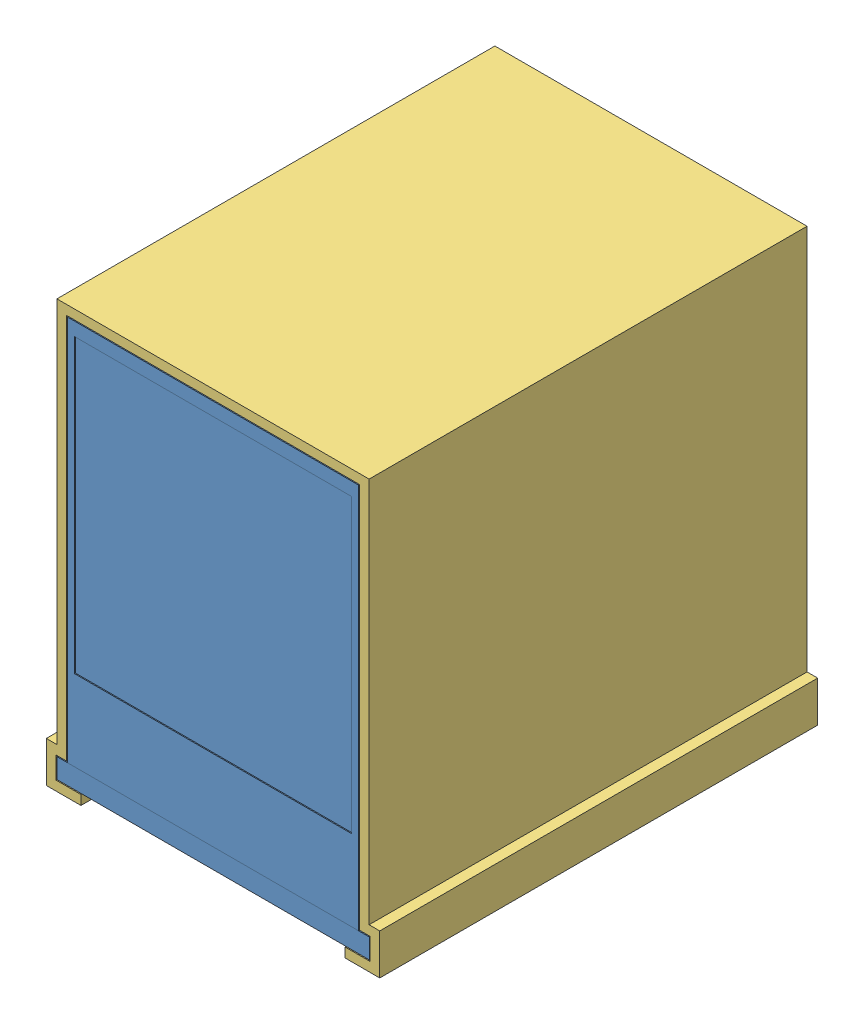
SolidWorks assembly Screen Backlight assembly, configuration Default. Lengths in mm.
Overall size (33.69 43.12 44.25).
3 component instances, 3 part files, 7 mates.
Components (placement in the parent):
- Screen-1: Screen [Default] at origin size (31.57 41 44.25)
- Led Panel-1: Led Panel [Default] at (0 19.95 -36.25) size (28.1 38.1 9.75)
- LED Panel Bracket v1-1: LED Panel Bracket v1 [Default] at origin size (33.69 43.12 44.25)
Mates (geometry in assembly coordinates):
- Coincident1: coincident: plane of ? through (-14.71 39 -2.56) normal (0 1 0); plane of Led Panel-1 through (-14.05 39 -34.75) normal (0 1 0)
- Width1: width: plane of ? through (-14.71 39 -2.56) normal (-1 0 0); plane of ? through (14.71 39 -2.56) normal (1 0 0); plane of Led Panel-1 through (-14.05 0.9 -34.75) normal (-1 0 0); plane of Led Panel-1 through (14.05 0.9 -34.75) normal (1 0 0)
- Distance1: distance = 8 mm: plane of Led Panel-1 through (0 19.95 -36.25) normal (0 0 -1); plane of ? through (-15.785 -2 -44.25) normal (0 0 -1)
- InPlace1: in place: plane of ? through (-15.785 -2 0) normal (0 0 1); plane of ? through (0 0 0) normal (0 0 1); moOrthogonalPlaneRef_w of ? through (-15.785 -2 0) normal (0 0 1); plane of ? through (0 0 0) normal (0 1 0); plane of ? through (-15.785 -2 0) normal (0 0 1); plane of ? through (0 0 0) normal (1 0 0); plane of ? through (-15.785 -2 0) normal (0 0 1); unknown of ?
- Coincident2: coincident: plane of assembly; plane of assembly; plane of Screen-1; plane of LED Panel Bracket v1-1
- Coincident3: coincident: plane of ? through (0 0 0) normal (0 1 0); plane of ? through (0 0 0) normal (0 1 0)
- Coincident4: coincident: plane of ? through (0 0 0) normal (-1 0 0); plane of ? through (0 0 0) normal (1 0 0)
